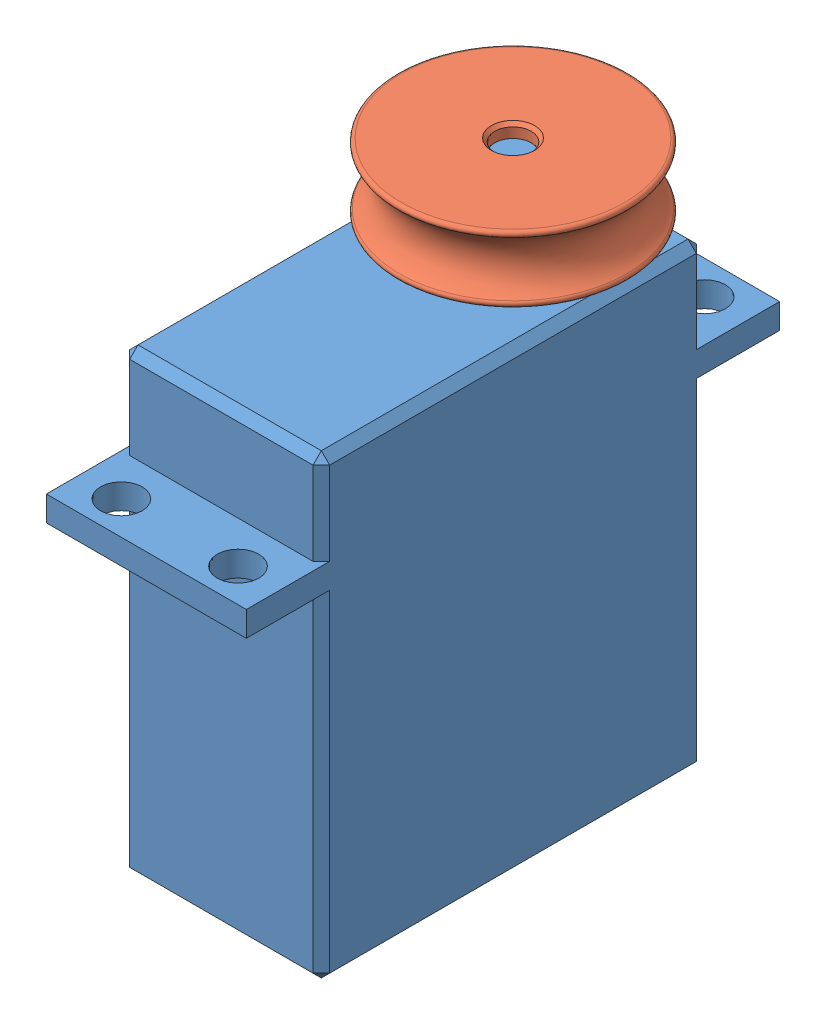
SolidWorks assembly ServoAssem, configuration Default. Lengths in mm.
Overall size (13.8 32.4 32).
2 component instances, 2 part files, 3 mates.
Components (placement in the parent):
- AGFRC Micro Servo-1: AGFRC Micro Servo [Default] at origin size (12 31.6 32)
- Pulley-1: Pulley [Default] at (0 28.4 5.5) x (1 0 0) z (0 -1 0) size (13.8 13.8 4)
Mates (geometry in assembly coordinates):
- Concentric1: concentric aligned: cylinder of AGFRC Micro Servo-1 through (0 31.6 5.5) axis (0 -1 0) radius 2.45; cylinder of Pulley-1 through (0 28.4 5.5) axis (0 -1 0) radius 2.6
- Coincident1: coincident anti-aligned: plane of AGFRC Micro Servo-1 through (0 28.4 5.5) normal (0 1 0); plane of Pulley-1 through (7.6 28.4 5.5) normal (0 -1 0)
- Coincident2: coincident aligned: plane of Pulley-1 through (0 28.4 5.5) normal (1 0 0)
